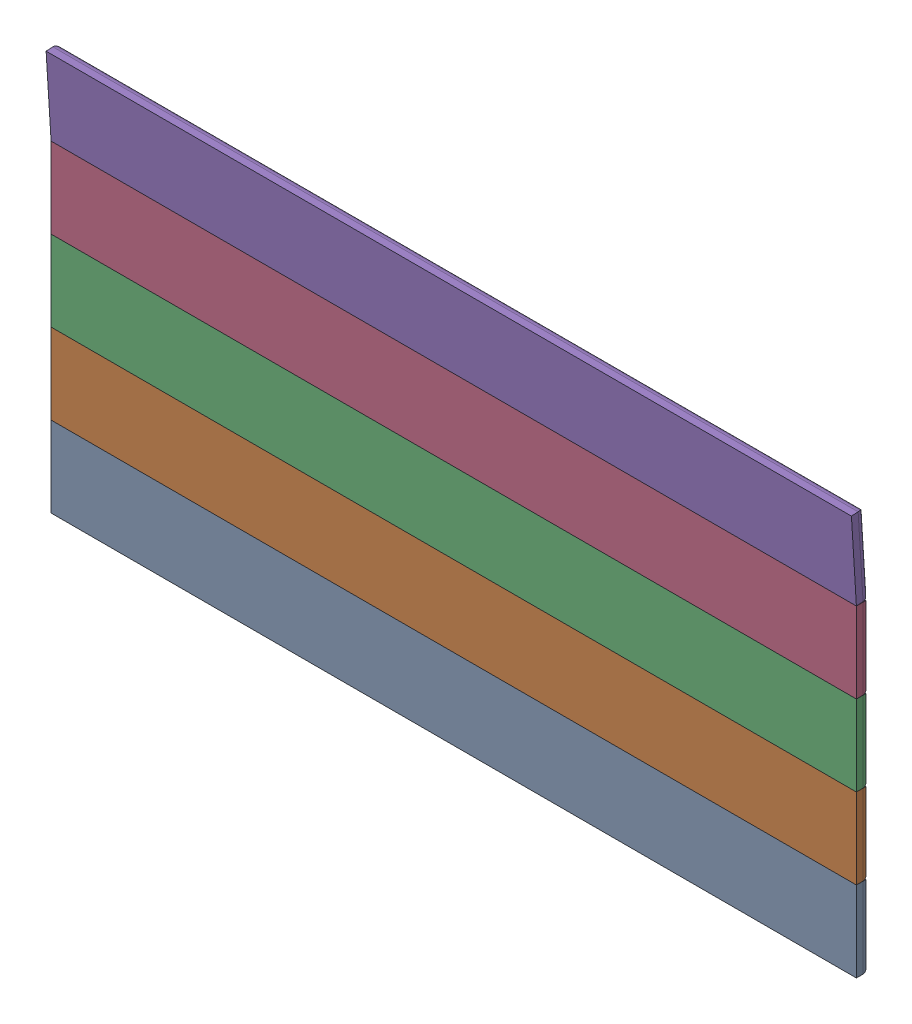
SolidWorks assembly Final Garage 2, configuration Default. Lengths in mm.
Overall size (6000 4350 4450).
5 component instances, 2 part files, 19 mates.
Components (placement in the parent):
- Garage Handle 2-2: Garage Handle 2 [Default] at (0 315.3177 0) x (-1 0 0) z (0 0 -1) size (6000 600 100)
- Garage Part 2-1: Garage Part 2 [Default] at (3000 1215.3177 -100) x (-1 0 0) z (0 0 -1) size (6000 600 100)
- Garage Part 2-2: Garage Part 2 [Default] at (3000 1815.3177 -100) x (-1 0 0) z (0 0 -1) size (6000 600 100)
- Garage Part 2-3: Garage Part 2 [Default] at (3000 2415.3177 -100) x (-1 0 0) z (0 0 -1) size (6000 600 100)
- Garage Part 2-4: Garage Part 2 [Default] at (3000 3020.9223 -81.2761) x (-1 0 0) z (0 0.061776 -0.99809) size (6000 600 100)
Mates (geometry in assembly coordinates):
- Coincident1: coincident anti-aligned: line of Garage Handle 2-2 through (0 915.3177 0) axis (1 0 0); line of Garage Part 2-1 through (6000 915.3177 0) axis (-1 0 0)
- Coincident2: coincident anti-aligned: line of Garage Part 2-1 through (0 1515.3177 0) axis (1 0 0); line of Garage Part 2-2 through (6000 1515.3177 0) axis (-1 0 0)
- Coincident3: coincident anti-aligned: line of Garage Part 2-2 through (0 2115.3177 0) axis (1 0 0); line of Garage Part 2-3 through (6000 2115.3177 0) axis (-1 0 0)
- Coincident4: coincident anti-aligned: line of Garage Part 2-3 through (0 2715.3177 0) axis (1 0 0); line of Garage Part 2-4 through (6000 2715.3177 0) axis (-1 0 0)
- Coincident5: coincident: point of Garage Part 2-3; point of Garage Part 2-4
- Coincident6: coincident: point of Garage Part 2-2; point of Garage Part 2-3
- Coincident7: coincident: point of Garage Part 2-1; point of Garage Part 2-2
- Coincident8: coincident: point of Garage Handle 2-2; point of Garage Part 2-1
- Coincident10: coincident aligned: plane of Garage Part 2-3 through (6000 2115.3177 0) normal (1 0 0); plane of Garage Part 2-4 through (6000 2715.3177 0) normal (1 0 0)
- Coincident11: coincident aligned: plane of Garage Part 2-2 through (6000 1515.3177 0) normal (1 0 0); plane of Garage Part 2-4 through (6000 2715.3177 0) normal (1 0 0)
- Coincident12: coincident aligned: plane of Garage Part 2-1 through (6000 915.3177 0) normal (1 0 0); plane of Garage Part 2-4 through (6000 2715.3177 0) normal (1 0 0)
- Coincident13: coincident aligned: plane of Garage Handle 2-2 through (6000 315.3177 -100) normal (1 0 0); plane of Garage Part 2-4 through (6000 2715.3177 0) normal (1 0 0)
- Parallel1: parallel aligned: plane of Garage Part 2-4 through (6000 2715.3177 0) normal (1 0 0)
- Coincident14: coincident: unknown of Garage Handle 2-2
- Coincident15: coincident: unknown of Garage Part 2-1
- Coincident16: coincident: unknown of Garage Part 2-1
- Coincident17: coincident: unknown of Garage Part 2-2
- Coincident18: coincident: unknown of Garage Part 2-4
- Coincident19: coincident: unknown of Garage Part 2-4
